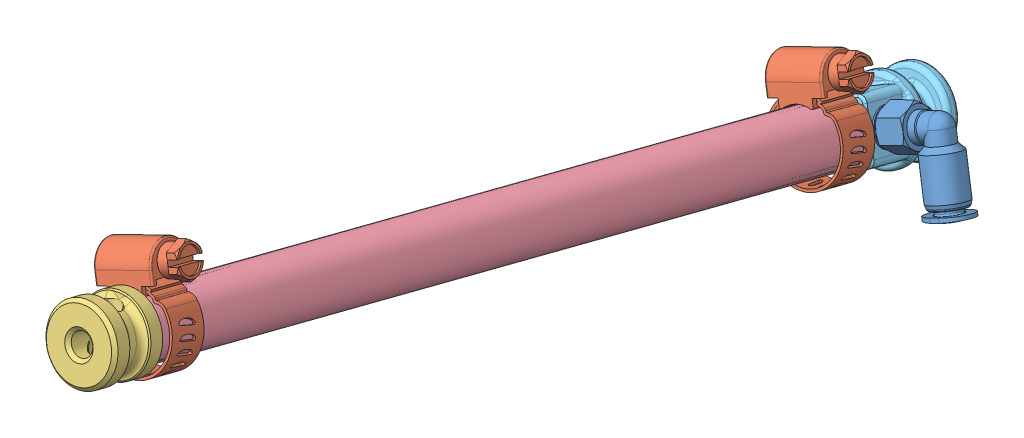
SolidWorks assembly AARL_QR_RL_MA_GN, configuration Default. Lengths in mm.
Overall size (41.03 81.75 208.64).
6 component instances, 5 part files, 13 mates.
Components (placement in the parent):
- AARL_Puppy_18_02_57_010-QSML-M3-4-1: AARL_Puppy_18_02_57_010-QSML-M3-4 [Default] at (-134.1154 39.2681 -38.3199) x (0.402613 -0.884632 0.235222) z (-0.914917 -0.380811 0.13383) size (20.32 8 18.9)
- AARL_Puppy_18_02_57_011-5388K140_Hose-Clamp-1: AARL_Puppy_18_02_57_011-5388K140_Hose-Clamp [5388K14] at (-150.1667 35.085 -26.5781) x (0.914917 0.380811 -0.13383) z (0.028815 0.26909 0.962684) size (19.43 23.71 9.91)
- AARL_Puppy_18_02_57_011-5388K140_Hose-Clamp-2: AARL_Puppy_18_02_57_011-5388K140_Hose-Clamp [5388K14] at (-145.3288 80.2636 135.0508) x (0.914917 0.380811 -0.13383) z (0.028815 0.26909 0.962684) size (19.43 23.71 9.91)
- AARL_QR_PN_EP_002-1: AARL_QR_PN_EP_002 [Default] at (-145.1861 81.5964 139.8189) x (0.090534 -0.959828 0.265582) z (-0.995476 -0.079503 0.052019) size (15.88 25.4 15.88)
- BPA main body 7INin-1: BPA main body 7INin [Resting] at (-147.7477 57.6743 54.2364) x (-0.179115 0.948886 -0.259872) z (-0.983406 -0.164943 0.07554) size (12.7 177.8 12.7)
- AARL_QR_PN_EP_500-1: AARL_QR_PN_EP_500 [Default] at (-150.6754 30.3347 -43.5723) x (0.914917 0.380811 -0.13383) z (-0.402613 0.884632 -0.235222) size (17.14 33.02 17.14)
Mates (geometry in assembly coordinates):
- Coincident8: coincident aligned: plane of AARL_Puppy_18_02_57_011-5388K140_Hose-Clamp-1 through (-148.4772 46.5562 -29.8351) normal (0.914917 0.380811 -0.13383); plane of AARL_Puppy_18_02_57_011-5388K140_Hose-Clamp-2 through (-143.6393 91.7348 131.7938) normal (0.914917 0.380811 -0.13383)
- Coincident9: coincident anti-aligned: plane of AARL_Puppy_18_02_57_011-5388K140_Hose-Clamp-2 through (-145.1861 81.5964 139.8189) normal (0.028815 0.26909 0.962684); plane of AARL_QR_PN_EP_002-1 through (-144.7908 77.4062 140.9784) normal (-0.028815 -0.26909 -0.962684)
- Concentric4: concentric aligned: cylinder of AARL_Puppy_18_02_57_011-5388K140_Hose-Clamp-1 through (-150.0523 36.1529 -22.7574) axis (-0.028815 -0.26909 -0.962684) radius 8.5217; cylinder of BPA main body 7INin-1 through (-148.0822 54.5505 43.061) axis (-0.028815 -0.26909 -0.962684) radius 6.35
- Concentric5: concentric aligned: cylinder of AARL_Puppy_18_02_57_011-5388K140_Hose-Clamp-2 through (-145.2144 81.3316 138.8714) axis (-0.028815 -0.26909 -0.962684) radius 8.5217; cylinder of BPA main body 7INin-1 through (-148.0822 54.5505 43.061) axis (-0.028815 -0.26909 -0.962684) radius 6.35
- Concentric6: concentric aligned: circle of AARL_QR_PN_EP_002-1; cylinder of BPA main body 7INin-1 through (-148.0822 54.5505 43.061) axis (-0.028815 -0.26909 -0.962684) radius 6.35
- Coincident11: coincident anti-aligned: plane of AARL_QR_PN_EP_002-1 through (-144.7908 77.4062 140.9784) normal (-0.028815 -0.26909 -0.962684); plane of BPA main body 7INin-1 through (-146.3235 87.6219 138.1688) normal (0.028815 0.26909 0.962684)
- Concentric7: concentric aligned: cylinder of AARL_Puppy_18_02_57_010-QSML-M3-4-1 through (-144.6369 34.8888 -36.7808) axis (0.914917 0.380811 -0.13383) radius 1.5; cylinder of AARL_QR_PN_EP_500-1 through (-144.6369 34.8888 -36.7808) axis (0.914917 0.380811 -0.13383) radius 2.0193
- Coincident12: coincident aligned: plane of AARL_Puppy_18_02_57_010-QSML-M3-4-1 through (-144.6369 34.8888 -36.7808) normal (-0.914917 -0.380811 0.13383); circle of AARL_QR_PN_EP_500-1
- Concentric8: concentric anti-aligned: cylinder of BPA main body 7INin-1 through (-148.0822 54.5505 43.061) axis (-0.028815 -0.26909 -0.962684) radius 4.7625; cylinder of AARL_QR_PN_EP_500-1 through (-150.5381 31.6163 -38.9875) axis (0.028815 0.26909 0.962684) radius 2.3813
- Coincident13: coincident anti-aligned: plane of BPA main body 7INin-1 through (-151.1624 38.2712 -32.5839) normal (-0.028815 -0.26909 -0.962684); plane of AARL_QR_PN_EP_500-1 through (-158.6757 36.9514 -31.9901) normal (0.028815 0.26909 0.962684)
- Coincident14: coincident anti-aligned: plane of AARL_Puppy_18_02_57_011-5388K140_Hose-Clamp-1 through (-150.3094 33.7522 -31.3462) normal (-0.028815 -0.26909 -0.962684); plane of AARL_QR_PN_EP_500-1 through (-158.6757 36.9514 -31.9901) normal (0.028815 0.26909 0.962684)
- Coincident15: coincident aligned: plane of AARL_Puppy_18_02_57_011-5388K140_Hose-Clamp-1 through (-160.0966 41.7199 -28.1354) normal (-0.914917 -0.380811 0.13383); plane of AARL_QR_PN_EP_500-1 through (-159.0417 33.534 -44.2162) normal (-0.914917 -0.380811 0.13383)
- Parallel2: parallel aligned: plane of AARL_Puppy_18_02_57_010-QSML-M3-4-1 through (-139.2267 38.5422 -42.119) normal (-0.028815 -0.26909 -0.962684); plane of AARL_QR_PN_EP_500-1 through (-150.8949 28.2843 -50.908) normal (-0.028815 -0.26909 -0.962684)
